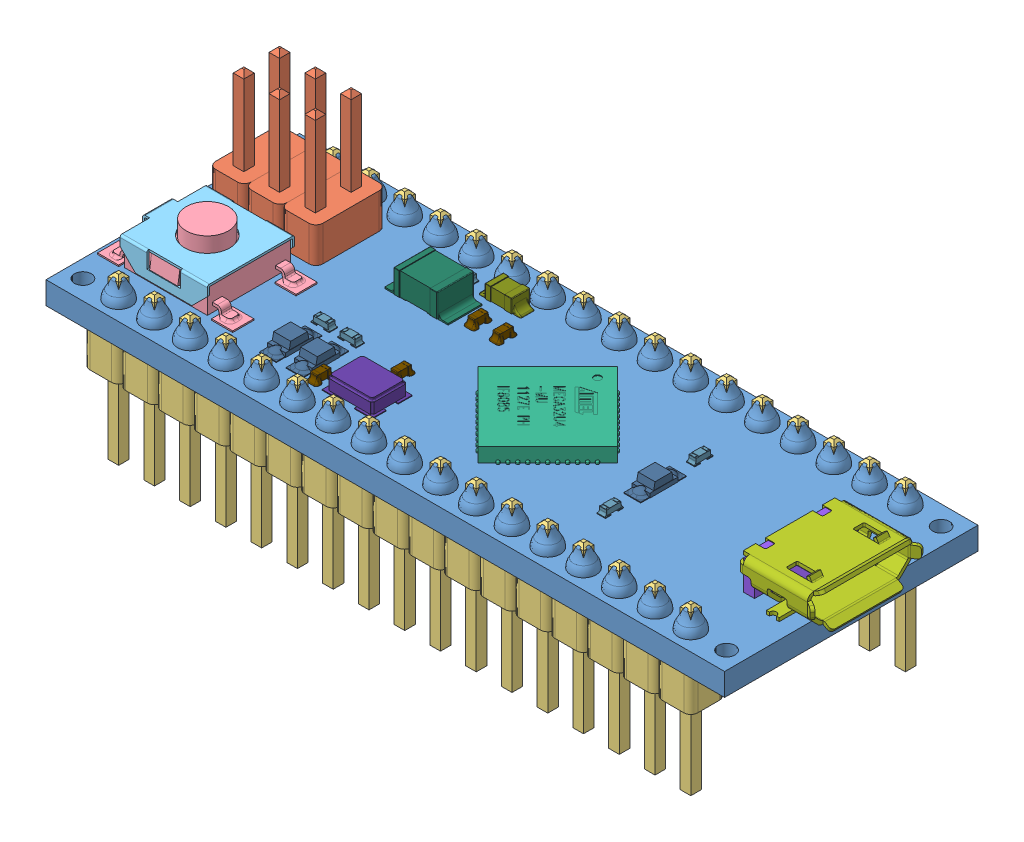
SolidWorks assembly ARDUINO MICRO, configuration Predeterminado. Lengths in mm.
Overall size (49.41 18.6 18).
54 component instances, 22 part files, 0 mates.
Components (placement in the parent):
- arduino micro board-1: arduino micro board [Predeterminado] at origin size (48.2 4.61 18)
- MICRO_2pin_header__02-1: MICRO_2pin_header__02 [Predeterminado] at (-1.27 1.6 -11.43) x (0 0 1) z (-1 0 0) size (5 11.75 2.54)
- MICRO_2pin_header__02-2: MICRO_2pin_header__02 [Predeterminado] at (1.27 1.6 -11.43) x (0 0 1) z (-1 0 0) size (5 11.75 2.54)
- MICRO_2pin_header__02-3: MICRO_2pin_header__02 [Predeterminado] at (3.81 1.6 -11.43) x (0 0 1) z (-1 0 0) size (5 11.75 2.54)
- MICRO_17pin_header__-1: MICRO_17pin_header__ [Predeterminado] at (0 0 -15.24) x (0 0 -1) z (-1 0 0) size (2.54 11.75 43.18)
- MICRO_17pin_header__-2: MICRO_17pin_header__ [Predeterminado] x (0 0 -1) z (-1 0 0) size (2.54 11.75 43.18)
- micro RESET BUTTON-1: micro RESET BUTTON [Predeterminado] at (1.3 1.6 -5) x (0 0 1) z (-1 0 0) size (6.2 3.1 9.6)
  - micro RESET CORE-1: micro RESET CORE [Predeterminado] at (0 0.1 0) x (-1 0 0) z (0 0 -1) size (6.2 3.1 9.6)
  - micro RESET-1: micro RESET [Predeterminado] at (0 0.1 0) x (0 0 1) z (-1 0 0) size (7.3 2 6.2)
- atmega32U4-1: atmega32U4 [Predeterminado] at (22.86 1.62 -7.62) x (-0.707107 0 -0.707107) z (0.707107 0 -0.707107) size (7.23 1.03 7.23)
- micro usb-1: micro usb [Predeterminado] at (45 1.85 -7.62) x (0 0 -1) z (1 0 0) size (8.01 3.25 5.93)
  - micro usb shell-1: micro usb shell [Predeterminado] at origin size (8.01 2.95 5.63)
  - micro usb internal-1: micro usb internal [Predeterminado] at (0 -0.25 0) size (6.9 2.9 4)
  - micro usb contact-1: micro usb contact [Predeterminado] at (1.3 -0.25 -0.1) size (0.2 1.3 4.4)
  - micro usb contact-2: micro usb contact [Predeterminado] at (0.65 -0.25 -0.1) size (0.2 1.3 4.4)
  - micro usb contact-3: micro usb contact [Predeterminado] at (0 -0.25 -0.1) size (0.2 1.3 4.4)
  - micro usb contact-4: micro usb contact [Predeterminado] at (-0.65 -0.25 -0.1) size (0.2 1.3 4.4)
  - micro usb contact-5: micro usb contact [Predeterminado] at (-1.3 -0.25 -0.1) size (0.2 1.3 4.4)
- MICRO_led2-1: MICRO_led2 [Predeterminado] at (8.8959 1.6 -3.3192) x (0 0 -1) z (1 0 0) size (3.24 0.8 1.31)
- MICRO_led2-2: MICRO_led2 [Predeterminado] at (41.529 0 -7.62) x (0 0 1) z (1 0 0) size (3.24 0.8 1.31)
- MICRO_led2-3: MICRO_led2 [Predeterminado] at (10.795 1.6 -3.3192) x (0 0 -1) z (1 0 0) size (3.24 0.8 1.31)
- MICRO_led2-4: MICRO_led2 [Predeterminado] at (30.48 1.6 -7.62) x (0 0 1) z (-1 0 0) size (3.24 0.8 1.31)
- micro_lmv358-1: micro_lmv358 [Predeterminado] at (39.7448 0 -11.938) x (1 0 0) z (0 0 -1) size (3.7 1.4 2.9)
- micro mf-msmf050-2-1: micro mf-msmf050-2 [Predeterminado] at (31.75 0 -3.937) x (1 0 0) z (0 0 -1) size (5.76 1.02 3.4)
- MICRO - reg-1: MICRO - reg [Predeterminado] at (10.16 0 -6.35) x (-1 0 0) z (0 0 1) size (6.5 1.69 8.3)
- MICRO_402 resistor-1: MICRO_402 resistor [Predeterminado] at (8.89 1.6 -5.715) x (-1 0 0) z (0 0 -1) size (1.3 0.45 0.63)
- MICRO_402 resistor-2: MICRO_402 resistor [Predeterminado] at (10.795 1.6 -5.715) size (1.3 0.45 0.63)
- MICRO_402 resistor-3: MICRO_402 resistor [Predeterminado] at (30.48 1.6 -10.795) x (0 0 -1) z (1 0 0) size (1.3 0.45 0.63)
- MICRO_402 resistor-4: MICRO_402 resistor [Predeterminado] at (30.48 1.6 -4.445) x (0 0 1) z (-1 0 0) size (1.3 0.45 0.63)
- MICRO_402 resistor-5: MICRO_402 resistor [Predeterminado] at (11.049 1.6 -13.589) x (-1 0 0) z (0 0 -1) size (1.3 0.45 0.63)
- micro solid tantalum cap 22u-1: micro solid tantalum cap 22u [Predeterminado] at (11.049 1.6 -11.303) size (4.5 1.75 2.61)
- MH2029-300Y-1: MH2029-300Y [Predeterminado] at (13.97 1.6 -13.589) size (3.01 1.06 1.31)
- micro_crystal 3.2 x 2.5-1: micro_crystal 3.2 x 2.5 [Predeterminado] at (14.605 1.65 -3.048) size (3.55 1 2.85)
- c0402-1: c0402 [Predeterminado] at (14.224 1.6 -11.303) x (0 0 1) z (-1 0 0) size (1.41 0.56 0.81)
- c0402-2: c0402 [Predeterminado] at (14.732 1.6 -5.334) x (0 0 1) z (-1 0 0) size (1.41 0.56 0.81)
- c0402-3: c0402 [Predeterminado] at (12.065 1.6 -2.286) x (0 0 1) z (-1 0 0) size (1.41 0.56 0.81)
- c0402-4: c0402 [Predeterminado] at (16.002 1.6 -11.303) x (0 0 1) z (-1 0 0) size (1.41 0.56 0.81)
- MICRO_402 resistor-6: MICRO_402 resistor [Predeterminado] at (5.5 0 -9.525) x (0 0 -1) z (-1 0 0) size (1.3 0.45 0.63)
- c0402-5: c0402 [Predeterminado] at (6.6 0 -9.525) x (0 0 1) z (1 0 0) size (1.41 0.56 0.81)
- c0402-6: c0402 [Predeterminado] at (3.81 0 -8.509) x (1 0 0) z (0 0 -1) size (1.41 0.56 0.81)
- c0402-7: c0402 [Predeterminado] at (22.205 0 -11.6714) x (0.707107 0 0.707107) z (0.707107 0 -0.707107) size (1.41 0.56 0.81)
- c0402-8: c0402 [Predeterminado] at (17.653 0 -7.62) x (1 0 0) z (0 0 -1) size (1.41 0.56 0.81)
- c0402-9: c0402 [Predeterminado] at (17.653 0 -9.525) x (1 0 0) z (0 0 -1) size (1.41 0.56 0.81)
- MICRO_402 resistor-7: MICRO_402 resistor [Predeterminado] at (19.304 0 -9.0805) x (-0.707107 0 -0.707107) z (-0.707107 0 0.707107) size (1.3 0.45 0.63)
- MICRO_220 RESISTOR PACK-1: MICRO_220 RESISTOR PACK [Predeterminado] at (33.2803 0 -7.62) x (0 0 -1) z (-1 0 0) size (3.2 0.46 2)
- c0402-10: c0402 [Predeterminado] at (43.434 0 -7.62) x (0 0 -1) z (-1 0 0) size (1.41 0.56 0.81)
- MICRO_402 resistor-8: MICRO_402 resistor [Predeterminado] at (40.132 0 -7.62) x (0 0 -1) z (-1 0 0) size (1.3 0.45 0.63)
- micro ssot3-1: micro ssot3 [Predeterminado] at (13.97 0 -12.0904) x (0 0 -1) z (-1 0 0) size (3 1.13 3.09)
- micro ssot3-2: micro ssot3 [Predeterminado] at (6.731 0 -12.0904) x (0 0 1) z (1 0 0) size (3 1.13 3.09)
- micro solid tantalum cap 22u-2: micro solid tantalum cap 22u [Predeterminado] at (39.497 0 -2.921) x (-1 0 0) z (0 0 1) size (4.5 1.75 2.61)
- c0402-11: c0402 [Predeterminado] at (35.1436 0 -12.954) x (1 0 0) z (0 0 -1) size (1.41 0.56 0.81)
- CG0603MLC-05E-1: CG0603MLC-05E [Predeterminado] at (36.576 0 -8.763) x (0 0 -1) z (-1 0 0) size (3 0.82 1)
- CG0603MLC-05E-2: CG0603MLC-05E [Predeterminado] at (38.227 0 -8.763) x (0 0 -1) z (-1 0 0) size (3 0.82 1)
- MICRO_DIODE CD1206-S01575-1: MICRO_DIODE CD1206-S01575 [Predeterminado] at (2.159 0 -5.588) x (-1 0 0) z (0 0 1) size (4.4 0.79 1.8)
